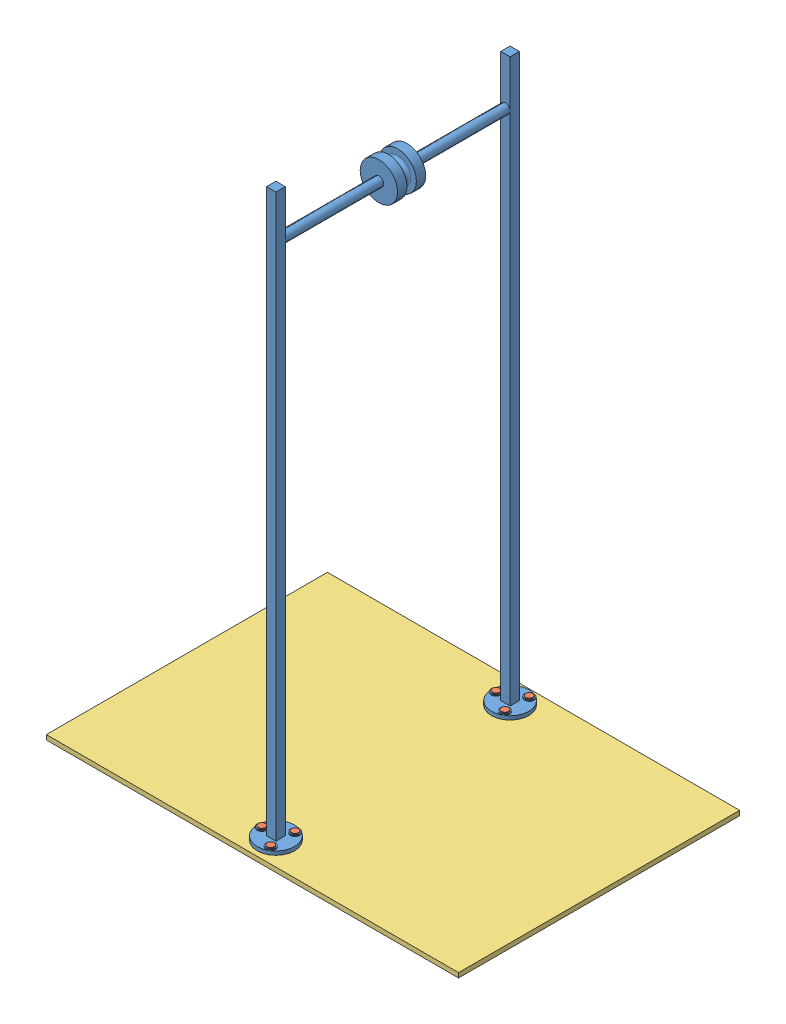
SolidWorks assembly project, configuration Default. Lengths in mm.
Overall size (1117.6 1546.86 762).
8 component instances, 3 part files, 19 mates.
Components (placement in the parent):
- project main setup-1: project main setup [Default] at (63.6047 132.3867 1379.0583) size (101.6 1534.16 736.6)
- Project -nut boltu-1: Project -nut boltu [Default] at (82.6547 119.6867 1028.5627) size (19.05 27.94 19.05)
- Project -nut boltu-2: Project -nut boltu [Default] at (82.6547 119.6867 1729.5539) size (19.05 27.94 19.05)
- Project -nut boltu-3: Project -nut boltu [Default] at (25.5047 119.6867 1061.5583) x (0.994551 0 -0.10425) z (0.10425 0 0.994551) size (19.05 27.94 19.05)
- Project -nut boltu-4: Project -nut boltu [Default] at (82.6547 119.6867 1094.5539) x (0.444899 0 0.895581) z (-0.895581 0 0.444899) size (19.05 27.94 19.05)
- Project -nut boltu-5: Project -nut boltu [Default] at (25.5047 119.6867 1696.5583) x (-0.068077 0 0.99768) z (-0.99768 0 -0.068077) size (19.05 27.94 19.05)
- Project -nut boltu-6: Project -nut boltu [Default] at (82.6547 119.6867 1663.5627) size (19.05 27.94 19.05)
- Project_base-1: Project_base [Default] at (63.6047 132.3867 1379.0583) size (1117.6 12.7 762)
Mates (geometry in assembly coordinates):
- Concentric1: concentric anti-aligned: circle of project main setup-1; cylinder of Project -nut boltu-1 through (82.6547 145.0867 1028.5627) axis (0 -1 0) radius 6.35
- Coincident2: coincident anti-aligned: plane of project main setup-1 through (82.6547 145.0867 1028.5627) normal (0 1 0); plane of Project -nut boltu-1 through (82.6547 145.0867 1028.5627) normal (0 -1 0)
- Concentric2: concentric aligned: cylinder of project main setup-1 through (82.6547 142.5467 1094.5539) axis (0 -1 0) radius 6.35; cylinder of Project -nut boltu-4 through (82.6547 145.0867 1094.5539) axis (0 -1 0) radius 6.35
- Coincident3: coincident anti-aligned: plane of project main setup-1 through (82.6547 145.0867 1094.5539) normal (0 1 0); plane of Project -nut boltu-4 through (82.6547 145.0867 1094.5539) normal (0 -1 0)
- Concentric3: concentric aligned: cylinder of project main setup-1 through (25.5047 142.5467 1061.5583) axis (0 -1 0) radius 6.35; cylinder of Project -nut boltu-3 through (25.5047 145.0867 1061.5583) axis (0 -1 0) radius 6.35
- Coincident4: coincident anti-aligned: plane of project main setup-1 through (25.5047 145.0867 1061.5583) normal (0 1 0); plane of Project -nut boltu-3 through (25.5047 145.0867 1061.5583) normal (0 -1 0)
- Concentric4: concentric aligned: cylinder of project main setup-1 through (25.5047 142.5467 1696.5583) axis (0 -1 0) radius 6.35; cylinder of Project -nut boltu-5 through (25.5047 145.0867 1696.5583) axis (0 -1 0) radius 6.35
- Coincident5: coincident anti-aligned: plane of project main setup-1 through (25.5047 145.0867 1696.5583) normal (0 1 0); plane of Project -nut boltu-5 through (25.5047 145.0867 1696.5583) normal (0 -1 0)
- Concentric5: concentric aligned: cylinder of project main setup-1 through (82.6547 142.5467 1663.5627) axis (0 -1 0) radius 6.35; cylinder of Project -nut boltu-6 through (82.6547 145.0867 1663.5627) axis (0 -1 0) radius 6.35
- Coincident6: coincident anti-aligned: plane of project main setup-1 through (82.6547 145.0867 1663.5627) normal (0 1 0); plane of Project -nut boltu-6 through (82.6547 145.0867 1663.5627) normal (0 -1 0)
- Concentric6: concentric aligned: cylinder of project main setup-1 through (82.6547 142.5467 1729.5539) axis (0 -1 0) radius 6.35; cylinder of Project -nut boltu-2 through (82.6547 145.0867 1729.5539) axis (0 -1 0) radius 6.35
- Coincident7: coincident anti-aligned: plane of project main setup-1 through (82.6547 145.0867 1729.5539) normal (0 1 0); plane of Project -nut boltu-2 through (82.6547 145.0867 1729.5539) normal (0 -1 0)
- Concentric7: concentric anti-aligned: cylinder of Project -nut boltu-3 through (25.5047 145.0867 1061.5583) axis (0 -1 0) radius 6.35; cylinder of Project_base-1 through (25.5047 119.6867 1061.5583) axis (0 1 0) radius 6.35
- Coincident9: coincident anti-aligned: cylinder of Project -nut boltu-4 through (82.6547 145.0867 1094.5539) axis (0 -1 0) radius 6.35; circle of Project_base-1
- Concentric8: concentric anti-aligned: cylinder of Project -nut boltu-1 through (82.6547 145.0867 1028.5627) axis (0 -1 0) radius 6.35; cylinder of Project_base-1 through (82.6547 119.6867 1028.5627) axis (0 1 0) radius 6.35
- Concentric9: concentric anti-aligned: cylinder of Project -nut boltu-5 through (25.5047 145.0867 1696.5583) axis (0 -1 0) radius 6.35; cylinder of Project_base-1 through (25.5047 119.6867 1696.5583) axis (0 1 0) radius 6.35
- Concentric10: concentric anti-aligned: cylinder of Project -nut boltu-6 through (82.6547 145.0867 1663.5627) axis (0 -1 0) radius 6.35; cylinder of Project_base-1 through (82.6547 119.6867 1663.5627) axis (0 1 0) radius 6.35
- Concentric11: concentric anti-aligned: cylinder of Project -nut boltu-2 through (82.6547 145.0867 1729.5539) axis (0 -1 0) radius 6.35; cylinder of Project_base-1 through (82.6547 119.6867 1729.5539) axis (0 1 0) radius 6.35
- Coincident10: coincident anti-aligned: plane of project main setup-1 through (63.6047 132.3867 1696.5583) normal (0 -1 0); plane of Project_base-1 through (63.6047 132.3867 1379.0583) normal (0 1 0)
